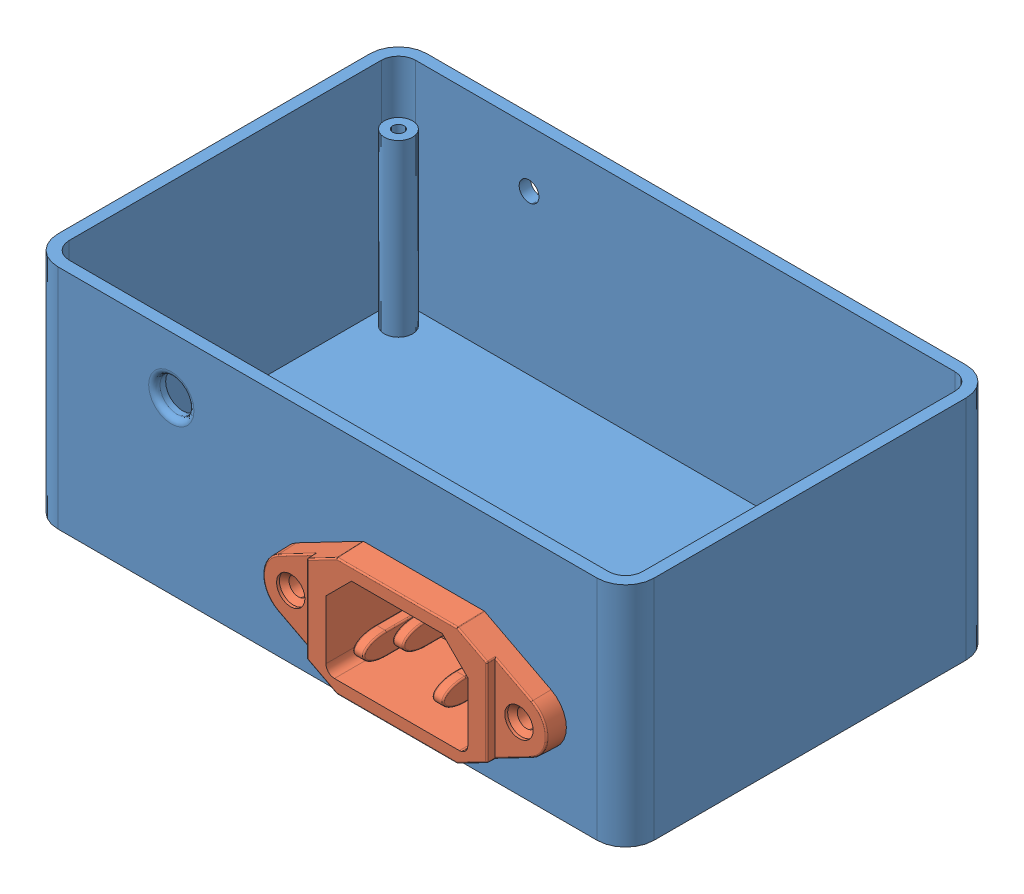
SolidWorks assembly montagem_caixa, configuration Default. Lengths in mm.
Overall size (105 40 70.05).
3 component instances, 3 part files, 7 mates.
Components (placement in the parent):
- box-1: box [Default] at origin size (105 40 65)
- cover-1: cover [Default] at (0 40 0) x (1 0 0) z (0 1 0) size (105 65 5) (hidden)
- Conector IEC C14 Entrada-1: Conector IEC C14 Entrada [Predeterminado] at (69.4766 14.4837 4.75) size (50.2 21.1 36.5)
Mates (geometry in assembly coordinates):
- InPlace1: in place: plane of box-1 through (0 40 0) normal (0 1 0); plane of cover-1 through (0 40 0) normal (0 1 0); moOrthogonalPlaneRef_w of box-1 through (0 40 0) normal (0 1 0); plane of cover-1 through (0 40 0) normal (0 0 -1); plane of box-1 through (0 40 0) normal (0 1 0); plane of cover-1 through (0 40 0) normal (1 0 0); plane of box-1 through (0 40 0) normal (0 1 0); unknown of cover-1
- Coincident1: coincident aligned: plane of box-1; plane of cover-1
- Coincident2: coincident aligned: moOrthogonalPlaneRef_w of box-1 through (0 40 0) normal (0 0 -1); plane of cover-1 through (0 40 0) normal (0 0 -1)
- Coincident3: coincident anti-aligned: moOrthogonalPlaneRef_w of box-1 through (0 40 0) normal (-1 0 0); plane of cover-1 through (0 40 0) normal (1 0 0)
- Concentric1: concentric aligned: cylinder of box-1 through (49.3766 14.4837 -65.001) axis (0 0 1) radius 1.5; cylinder of Conector IEC C14 Entrada-1 through (49.3766 14.4837 3.35) axis (0 0 1) radius 1.65
- Concentric2: concentric aligned: cylinder of box-1 through (89.5766 14.4837 -65.001) axis (0 0 1) radius 1.5; cylinder of Conector IEC C14 Entrada-1 through (89.5766 14.4837 3.35) axis (0 0 1) radius 1.65
- Coincident1: coincident anti-aligned: plane of box-1 through (105 40 0) normal (0 0 1); plane of Conector IEC C14 Entrada-1 through (49.3766 14.4837 0) normal (0 0 -1)
